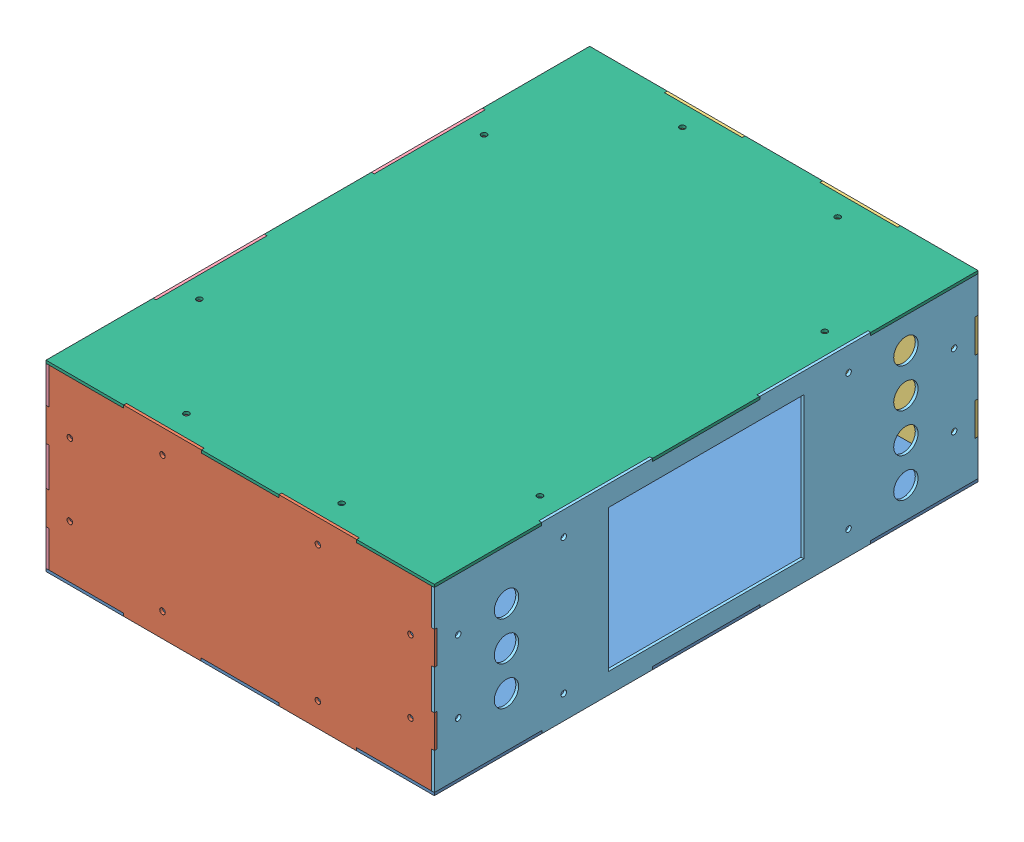
SolidWorks assembly Box, configuration Default. Lengths in mm.
Overall size (350 165 490).
6 component instances, 6 part files, 15 mates.
Components (placement in the parent):
- Bottom-1: Bottom [Default] at origin size (350 2.5 490)
- Front-1: Front [Default] at (0 82.5 242.5) size (350 165 2.5)
- Back-1: Back [Default] at (0 82.5 -245) size (350 165 2.5)
- Lat_Left-1: Lat_Left [Default] at (-175 82.5 0) size (2.5 165 490)
- Lat_Right-1: Lat_Right [Default] at (172.5 82.5 0) size (2.5 165 490)
- Top-1: Top [Default] at (0 162.5 0) size (350 2.5 490)
Mates (geometry in assembly coordinates):
- Coincident1: coincident aligned: plane of Bottom-1 through (-175 2.5 245) normal (0 0 1); plane of Front-1 through (0 82.5 245) normal (0 0 1)
- Coincident2: coincident aligned: plane of Bottom-1 through (175 2.5 -245) normal (1 0 0); plane of Front-1 through (175 130 245) normal (1 0 0)
- Coincident3: coincident aligned: plane of Bottom-1 through (0 0 0) normal (0 -1 0); plane of Front-1 through (105 0 245) normal (0 -1 0)
- Coincident4: coincident aligned: plane of Bottom-1 through (0 0 0) normal (0 -1 0); plane of Back-1 through (105 0 -242.5) normal (0 -1 0)
- Coincident5: coincident aligned: plane of Bottom-1 through (-175 2.5 -245) normal (0 0 -1); plane of Back-1 through (0 82.5 -245) normal (0 0 -1)
- Coincident6: coincident aligned: plane of Bottom-1 through (175 2.5 -245) normal (1 0 0); plane of Back-1 through (175 35 -242.5) normal (1 0 0)
- Coincident7: coincident aligned: plane of Bottom-1 through (0 0 0) normal (0 -1 0); plane of Lat_Left-1 through (-172.5 0 -148.3333) normal (0 -1 0)
- Coincident8: coincident aligned: plane of Bottom-1 through (-175 2.5 -245) normal (-1 0 0); plane of Lat_Left-1 through (-175 82.5 0) normal (-1 0 0)
- Coincident9: coincident aligned: plane of Bottom-1 through (-175 2.5 245) normal (0 0 1); plane of Lat_Left-1 through (-172.5 2.5 245) normal (0 0 1)
- Coincident10: coincident aligned: plane of Bottom-1 through (175 2.5 -245) normal (1 0 0); plane of Lat_Right-1 through (175 82.5 0) normal (1 0 0)
- Coincident11: coincident aligned: plane of Bottom-1 through (-175 2.5 245) normal (0 0 1); plane of Lat_Right-1 through (175 2.5 245) normal (0 0 1)
- Coincident12: coincident aligned: plane of Bottom-1 through (0 0 0) normal (0 -1 0); plane of Lat_Right-1 through (175 0 148.3333) normal (0 -1 0)
- Coincident13: coincident aligned: plane of Lat_Right-1 through (175 82.5 0) normal (1 0 0); plane of Top-1 through (175 165 -245) normal (1 0 0)
- Coincident14: coincident aligned: plane of Front-1 through (0 82.5 245) normal (0 0 1); plane of Top-1 through (-175 165 245) normal (0 0 1)
- Coincident15: coincident aligned: plane of Front-1 through (105 165 245) normal (0 1 0); plane of Top-1 through (0 165 0) normal (0 1 0)
